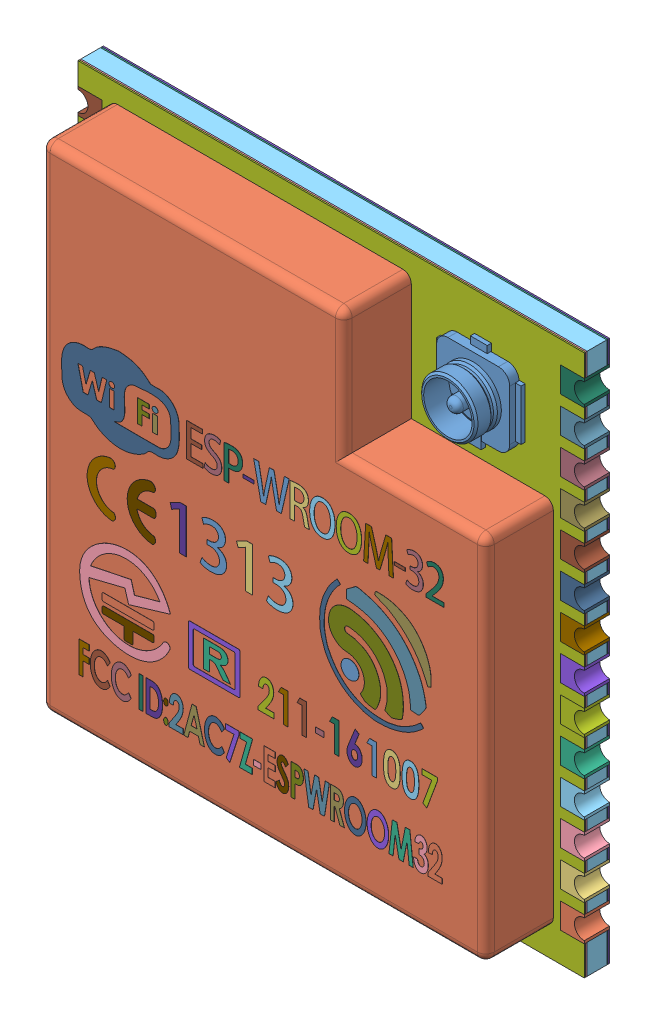
SolidWorks assembly ESP32 WROOMU, configuration По умолчанию. Lengths in mm.
Overall size (18 19.25 3.33).
111 component instances, 110 part files, 0 mates.
Components (placement in the parent):
- ESP32 WROOMU.step-1: ESP32 WROOMU.step [Default] at origin size (18 19.25 3.33)
  - U_FL-R-SMT.step-1: U_FL-R-SMT.step [Default] at (5.4 3.6 0.9) size (3 3.1 1.25)
  - ESP32 WROOMU.step-1: ESP32 WROOMU.step [Default] at origin size (0.85 0.9 0.9)
  - ESP32 WROOMU-0.step-1: ESP32 WROOMU-0.step [Default] at origin size (0.85 0.9 0.9)
  - ESP32 WROOMU-1.step-1: ESP32 WROOMU-1.step [Default] at origin size (0.85 0.9 0.9)
  - ESP32 WROOMU-2.step-1: ESP32 WROOMU-2.step [Default] at origin size (0.85 0.9 0.9)
  - ESP32 WROOMU-3.step-1: ESP32 WROOMU-3.step [Default] at origin size (0.85 0.9 0.9)
  - ESP32 WROOMU-4.step-1: ESP32 WROOMU-4.step [Default] at origin size (0.85 0.9 0.9)
  - ESP32 WROOMU-5.step-1: ESP32 WROOMU-5.step [Default] at origin size (0.85 0.9 0.9)
  - ESP32 WROOMU-6.step-1: ESP32 WROOMU-6.step [Default] at origin size (0.85 0.9 0.9)
  - ESP32 WROOMU-7.step-1: ESP32 WROOMU-7.step [Default] at origin size (0.85 0.9 0.9)
  - ESP32 WROOMU-8.step-1: ESP32 WROOMU-8.step [Default] at origin size (0.85 0.9 0.9)
  - ESP32 WROOMU-9.step-1: ESP32 WROOMU-9.step [Default] at origin size (0.85 0.9 0.9)
  - ESP32 WROOMU-10.step-1: ESP32 WROOMU-10.step [Default] at origin size (0.85 0.9 0.9)
  - ESP32 WROOMU-11.step-1: ESP32 WROOMU-11.step [Default] at origin size (0.85 0.9 0.9)
  - ESP32 WROOMU-12.step-1: ESP32 WROOMU-12.step [Default] at origin size (0.85 0.9 0.9)
  - ESP32 WROOMU-13.step-1: ESP32 WROOMU-13.step [Default] at origin size (0.85 0.9 0.9)
  - ESP32 WROOMU-14.step-1: ESP32 WROOMU-14.step [Default] at origin size (0.85 0.9 0.9)
  - ESP32 WROOMU-15.step-1: ESP32 WROOMU-15.step [Default] at origin size (0.85 0.9 0.9)
  - ESP32 WROOMU-16.step-1: ESP32 WROOMU-16.step [Default] at origin size (0.85 0.9 0.9)
  - ESP32 WROOMU-17.step-1: ESP32 WROOMU-17.step [Default] at origin size (0.85 0.9 0.9)
  - ESP32 WROOMU-18.step-1: ESP32 WROOMU-18.step [Default] at origin size (0.85 0.9 0.9)
  - ESP32 WROOMU-19.step-1: ESP32 WROOMU-19.step [Default] at origin size (0.85 0.9 0.9)
  - ESP32 WROOMU-20.step-1: ESP32 WROOMU-20.step [Default] at origin size (0.85 0.9 0.9)
  - ESP32 WROOMU-21.step-1: ESP32 WROOMU-21.step [Default] at origin size (0.85 0.9 0.9)
  - ESP32 WROOMU-22.step-1: ESP32 WROOMU-22.step [Default] at origin size (0.85 0.9 0.9)
  - ESP32 WROOMU-23.step-1: ESP32 WROOMU-23.step [Default] at origin size (0.85 0.9 0.9)
  - ESP32 WROOMU-24.step-1: ESP32 WROOMU-24.step [Default] at origin size (0.85 0.9 0.9)
  - ESP32 WROOMU-25.step-1: ESP32 WROOMU-25.step [Default] at origin size (0.85 0.9 0.9)
  - ESP32 WROOMU-26.step-1: ESP32 WROOMU-26.step [Default] at origin size (0.85 0.9 0.9)
  - ESP32 WROOMU-27.step-1: ESP32 WROOMU-27.step [Default] at origin size (0.9 0.85 0.9)
  - ESP32 WROOMU-28.step-1: ESP32 WROOMU-28.step [Default] at origin size (0.9 0.85 0.9)
  - ESP32 WROOMU-29.step-1: ESP32 WROOMU-29.step [Default] at origin size (0.9 0.85 0.9)
  - ESP32 WROOMU-30.step-1: ESP32 WROOMU-30.step [Default] at origin size (0.9 0.85 0.9)
  - ESP32 WROOMU-31.step-1: ESP32 WROOMU-31.step [Default] at origin size (0.9 0.85 0.9)
  - ESP32 WROOMU-32.step-1: ESP32 WROOMU-32.step [Default] at origin size (0.9 0.85 0.9)
  - ESP32 WROOMU-33.step-1: ESP32 WROOMU-33.step [Default] at origin size (0.9 0.85 0.9)
  - ESP32 WROOMU-34.step-1: ESP32 WROOMU-34.step [Default] at origin size (0.9 0.85 0.9)
  - ESP32 WROOMU-35.step-1: ESP32 WROOMU-35.step [Default] at origin size (0.9 0.85 0.9)
  - ESP32 WROOMU-36.step-1: ESP32 WROOMU-36.step [Default] at origin size (0.9 0.85 0.9)
  - ESP32 WROOMU-37.step-1: ESP32 WROOMU-37.step [Default] at origin size (18 19.25 0.05)
  - ESP32 WROOMU-38.step-1: ESP32 WROOMU-38.step [Default] at origin size (18 19.25 0.7)
  - ESP32 WROOMU-39.step-1: ESP32 WROOMU-39.step [Default] at origin size (18 19.25 0.05)
  - ESP32 WROOMU-40.step-1: ESP32 WROOMU-40.step [По умолчанию] at origin size (18 19.25 0.05)
  - ESP32 WROOMU-41.step-1: ESP32 WROOMU-41.step [Default] at origin size (18 19.25 0.06)
  - ESP32 WROOMU-42.step-1: ESP32 WROOMU-42.step [Default] at origin size (1 1.9 0)
  - ESP32 WROOMU-43.step-1: ESP32 WROOMU-43.step [Default] at origin size (4.33 2.98 0)
  - ESP32 WROOMU-44.step-1: ESP32 WROOMU-44.step [Default] at origin size (0.58 1.19 0)
  - ESP32 WROOMU-45.step-1: ESP32 WROOMU-45.step [Default] at origin size (0.16 0.58 0)
  - ESP32 WROOMU-46.step-1: ESP32 WROOMU-46.step [Default] at origin size (0.63 1.23 0)
  - ESP32 WROOMU-47.step-1: ESP32 WROOMU-47.step [Default] at origin size (0.21 0.19 0)
  - ESP32 WROOMU-48.step-1: ESP32 WROOMU-48.step [Default] at origin size (0.65 1.2 0)
  - ESP32 WROOMU-49.step-1: ESP32 WROOMU-49.step [Default] at origin size (0.42 0.8 0)
  - ESP32 WROOMU-50.step-1: ESP32 WROOMU-50.step [Default] at origin size (0.39 0.11 0)
  - ESP32 WROOMU-51.step-1: ESP32 WROOMU-51.step [Default] at origin size (1.84 0.69 0)
  - ESP32 WROOMU-52.step-1: ESP32 WROOMU-52.step [Default] at origin size (1.26 1.2 0)
  - ESP32 WROOMU-53.step-1: ESP32 WROOMU-53.step [Default] at origin size (1.84 0.27 0)
  - ESP32 WROOMU-54.step-1: ESP32 WROOMU-54.step [Default] at origin size (0.69 1.2 0)
  - ESP32 WROOMU-55.step-1: ESP32 WROOMU-55.step [Default] at origin size (3.24 4.04 0)
  - ESP32 WROOMU-56.step-1: ESP32 WROOMU-56.step [Default] at origin size (0.9 1.23 0.01)
  - ESP32 WROOMU-57.step-1: ESP32 WROOMU-57.step [Default] at origin size (0.96 0.95 0)
  - ESP32 WROOMU-58.step-1: ESP32 WROOMU-58.step [Default] at origin size (0.9 1.23 0.01)
  - ESP32 WROOMU-59.step-1: ESP32 WROOMU-59.step [Default] at origin size (1.83 1.49 0)
  - ESP32 WROOMU-60.step-1: ESP32 WROOMU-60.step [Default] at origin size (1.06 1.2 0)
  - ESP32 WROOMU-61.step-1: ESP32 WROOMU-61.step [Default] at origin size (3.7 3.7 0)
  - ESP32 WROOMU-62.step-1: ESP32 WROOMU-62.step [Default] at origin size (0.39 0.11 0)
  - ESP32 WROOMU-63.step-1: ESP32 WROOMU-63.step [Default] at origin size (2.01 2.03 0)
  - ESP32 WROOMU-64.step-1: ESP32 WROOMU-64.step [Default] at origin size (0.62 1.22 0)
  - ESP32 WROOMU-65.step-1: ESP32 WROOMU-65.step [Default] at origin size (2.84 2.87 0)
  - ESP32 WROOMU-66.step-1: ESP32 WROOMU-66.step [Default] at origin size (0.64 1.2 0)
  - ESP32 WROOMU-67.step-1: ESP32 WROOMU-67.step [Default] at origin size (2.67 2.67 0)
  - ESP32 WROOMU-68.step-1: ESP32 WROOMU-68.step [Default] at origin size (0.57 1.56 0)
  - ESP32 WROOMU-69.step-1: ESP32 WROOMU-69.step [Default] at origin size (1.03 1.9 0)
  - ESP32 WROOMU-70.step-1: ESP32 WROOMU-70.step [Default] at origin size (0.94 1.62 0)
  - ESP32 WROOMU-71.step-1: ESP32 WROOMU-71.step [Default] at origin size (0.51 1.13 0)
  - ESP32 WROOMU-72.step-1: ESP32 WROOMU-72.step [Default] at origin size (0.57 1.56 0)
  - ESP32 WROOMU-73.step-1: ESP32 WROOMU-73.step [Default] at origin size (0.52 1.16 0)
  - ESP32 WROOMU-74.step-1: ESP32 WROOMU-74.step [Default] at origin size (0.94 1.62 0)
  - ESP32 WROOMU-75.step-1: ESP32 WROOMU-75.step [Default] at origin size (0.86 1.1 0)
  - ESP32 WROOMU-76.step-1: ESP32 WROOMU-76.step [Default] at origin size (0.58 1.13 0)
  - ESP32 WROOMU-77.step-1: ESP32 WROOMU-77.step [Default] at origin size (0.76 1.16 0)
  - ESP32 WROOMU-78.step-1: ESP32 WROOMU-78.step [Default] at origin size (0.34 1.1 0)
  - ESP32 WROOMU-79.step-1: ESP32 WROOMU-79.step [Default] at origin size (0.76 1.16 0)
  - ESP32 WROOMU-80.step-1: ESP32 WROOMU-80.step [Default] at origin size (0.34 1.1 0)
  - ESP32 WROOMU-81.step-1: ESP32 WROOMU-81.step [Default] at origin size (0.5 1.1 0)
  - ESP32 WROOMU-82.step-1: ESP32 WROOMU-82.step [Default] at origin size (0.3 0.18 0)
  - ESP32 WROOMU-83.step-1: ESP32 WROOMU-83.step [Default] at origin size (0.9 1.1 0)
  - ESP32 WROOMU-84.step-1: ESP32 WROOMU-84.step [Default] at origin size (0.34 1.1 0)
  - ESP32 WROOMU-85.step-1: ESP32 WROOMU-85.step [Default] at origin size (0.44 1.1 0)
  - ESP32 WROOMU-86.step-1: ESP32 WROOMU-86.step [Default] at origin size (0.54 1.16 0)
  - ESP32 WROOMU-87.step-1: ESP32 WROOMU-87.step [Default] at origin size (0.45 1.16 0)
  - ESP32 WROOMU-88.step-1: ESP32 WROOMU-88.step [Default] at origin size (0.34 1.1 0)
  - ESP32 WROOMU-89.step-1: ESP32 WROOMU-89.step [Default] at origin size (0.39 1.1 0)
  - ESP32 WROOMU-90.step-1: ESP32 WROOMU-90.step [Default] at origin size (0.59 1.16 0)
  - ESP32 WROOMU-91.step-1: ESP32 WROOMU-91.step [Default] at origin size (0.25 0.18 0)
  - ESP32 WROOMU-92.step-1: ESP32 WROOMU-92.step [Default] at origin size (0.59 1.16 0)
  - ESP32 WROOMU-93.step-1: ESP32 WROOMU-93.step [Default] at origin size (0.47 1.1 0)
  - ESP32 WROOMU-94.step-1: ESP32 WROOMU-94.step [Default] at origin size (0.55 1.13 0)
  - ESP32 WROOMU-95.step-1: ESP32 WROOMU-95.step [Default] at origin size (0.48 1.13 0)
  - ESP32 WROOMU-96.step-1: ESP32 WROOMU-96.step [Default] at origin size (0.37 1.1 0)
  - ESP32 WROOMU-97.step-1: ESP32 WROOMU-97.step [Default] at origin size (0.71 1.16 0)
  - ESP32 WROOMU-98.step-1: ESP32 WROOMU-98.step [Default] at origin size (0.71 1.16 0)
  - ESP32 WROOMU-99.step-1: ESP32 WROOMU-99.step [Default] at origin size (0.73 1.1 0)
  - ESP32 WROOMU-100.step-1: ESP32 WROOMU-100.step [Default] at origin size (0.71 1.16 0)
  - ESP32 WROOMU-101.step-1: ESP32 WROOMU-101.step [Default] at origin size (0.51 1.13 0)
  - ESP32 WROOMU-102.step-1: ESP32 WROOMU-102.step [Default] at origin size (0.14 1.1 0)
  - ESP32 WROOMU-103.step-1: ESP32 WROOMU-103.step [Default] at origin size (0.16 0.24 0)
  - ESP32 WROOMU-104.step-1: ESP32 WROOMU-104.step [Default] at origin size (0.59 1.1 0)
  - ESP32 WROOMU-105.step-1: ESP32 WROOMU-105.step [Default] at origin size (0.16 0.24 0)
  - ESP32 WROOMU-106.step-1: ESP32 WROOMU-106.step [Default] at origin size (0.63 0.63 0)
  - ESP32 WROOMU-107.step-1: ESP32 WROOMU-107.step [Default] at origin size (15.8 17.6 2.4)
